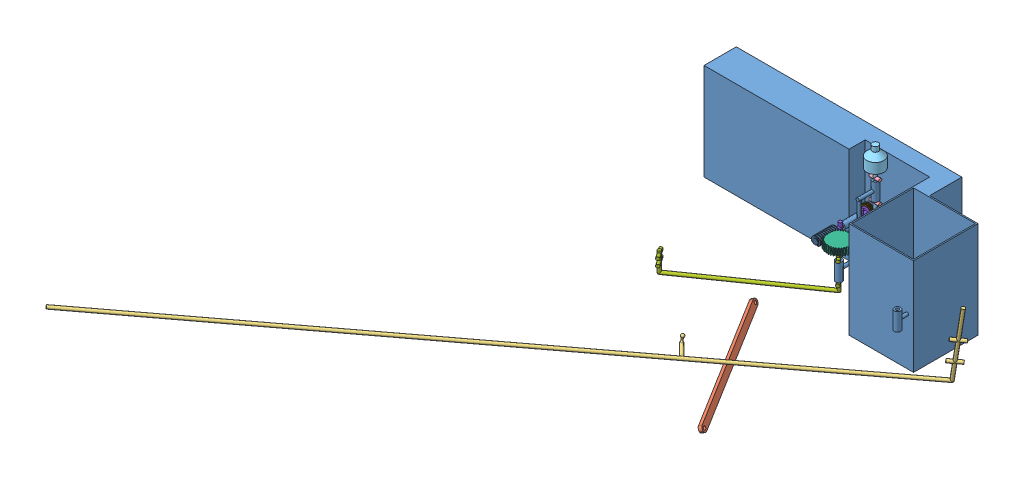
SolidWorks assembly SC q1 SW, configuration Défaut. Lengths in mm.
Overall size (1476.61 671.68 1746.65).
13 component instances, 10 part files, 6 mates.
Components (placement in the parent):
- Bati-1: Bati [Défaut] at (432 235 -197) x (-1 0 0) z (0 1 0) size (850 340 300)
- Bielle-2: Bielle [Défaut] at (401.8803 -166.7609 314.5163) x (-0.457257 0.208228 -0.864614) z (0.830078 0.448866 -0.330891) size (408 20 10)
- vantail-2: vantail [Défaut] at (874.8408 46.4684 7.9856) x (-0.68967 0.111644 0.715466) z (0.179247 0.983615 0.019297) size (2020 61.5 225)
- arbre moteur-2: arbre moteur [Défaut] at (432 292.5 -197) x (0 -1 0) z (-1 0 0) size (214.5 74.88 74.88)
  - arbre moteur-1: arbre moteur [Défaut] at origin size (150 10 30)
  - vis moteur-1: vis moteur [Défaut] at (122.5 0 0) x (0 -0.73755 -0.675292) z (-1 0 0) size (53 53 214.5)
- arbre sortie-1: arbre sortie [Défaut] at (449 165 -67) x (-0.573769 0 -0.819017) z (0 -1 0) size (74.27 442.1 142.5)
  - roue arbre sortie-1: roue arbre sortie [Défaut] at origin size (74.27 74.24 20)
  - arbre sortie + bras-1: arbre sortie + bras [Défaut] at (0 0 127.5) x (1 0 0) z (0 1 0) size (40 122.5 410)
- arbtre intermediaire-1: arbtre intermediaire [Défaut] at (408.4 165 -204.5) x (0 0 1) z (0 1 0) size (168.32 41.72 41.74)
  - arbre intermediaire-1: arbre intermediaire [Défaut] at origin size (153 30 30)
  - EngrHelicD3PA5418-1: EngrHelicD3PA5418 [Défaut] at (7.5 0 0) x (0 0 -1) z (1 0 0) size (41.74 41.72 11)
  - arbre-1: arbre [Défaut] at (137.8171 0 0) x (0 0 1) z (-1 0 0) size (27.87 26.95 65)
Mates (geometry in assembly coordinates):
- Coaxiale1: concentric anti-aligned: cylinder of Bati-1; cylinder of arbre moteur-2/vis moteur-1
- Tangent1: tangent anti-aligned: plane of Bati-1 through (432 262.5 -197) normal (0 1 0); cylinder of arbre moteur-2/arbre moteur-1
- Coaxiale2: concentric aligned: cylinder of Bati-1; cylinder of arbtre intermediaire-1/arbre intermediaire-1
- Tangent3: tangent anti-aligned: plane of Bati-1 through (408.4 165 -117) normal (0 0 1); cylinder of arbtre intermediaire-1/arbre intermediaire-1
- Coaxiale3: concentric anti-aligned: cylinder of Bati-1; cylinder of arbre sortie-1/arbre sortie + bras-1
- Tangent4: tangent anti-aligned: plane of Bati-1 through (449 120 -67) normal (0 1 0); cylinder of arbre sortie-1/arbre sortie + bras-1
